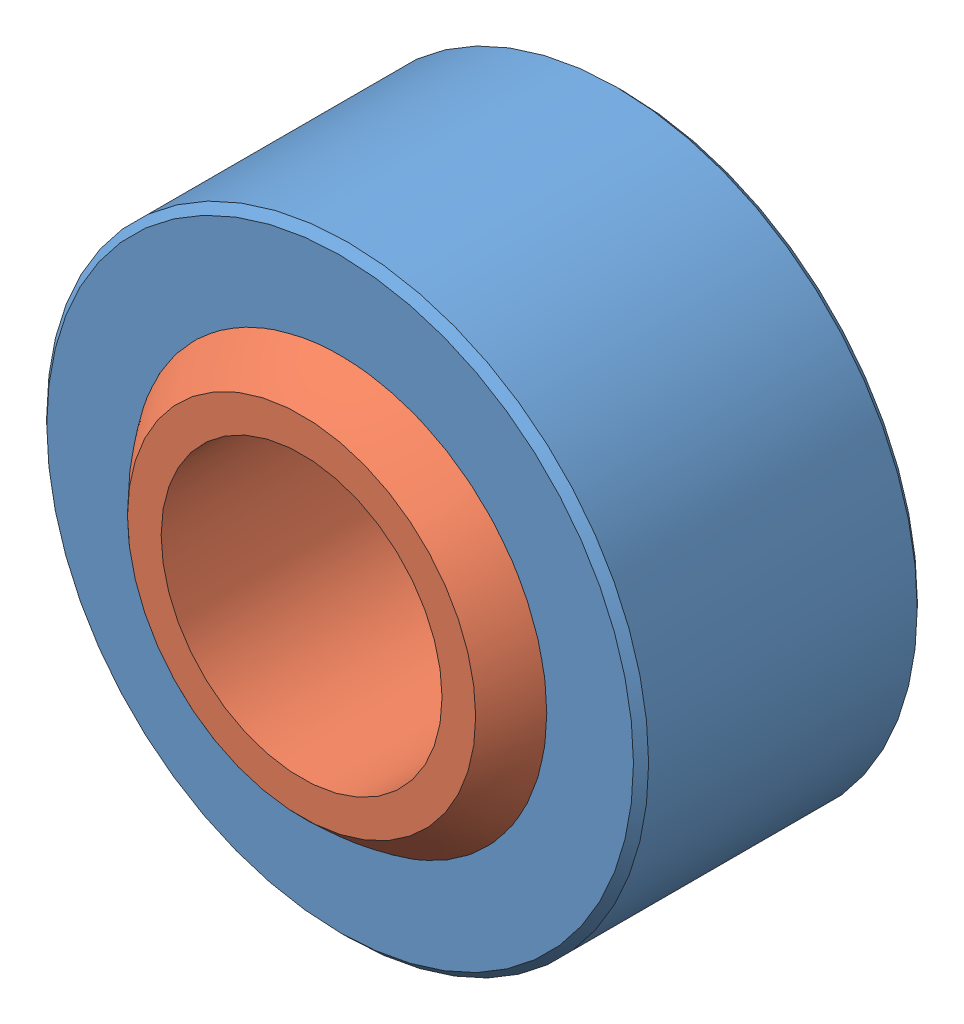
SolidWorks assembly SphericalBearing437in, configuration Default. Lengths in mm.
Overall size (23.81 23.81 14.27).
2 component instances, 2 part files, 1 mates.
Components (placement in the parent):
- SphericalBearing437Race-1: SphericalBearing437Race [Default] at origin size (23.81 23.81 11.23)
- SphericalBearing437Ball-1: SphericalBearing437Ball [Default] at origin size (19.84 19.84 14.27)
Mates (geometry in assembly coordinates):
- Concentric1: concentric: sphere of ?; unknown of ?
